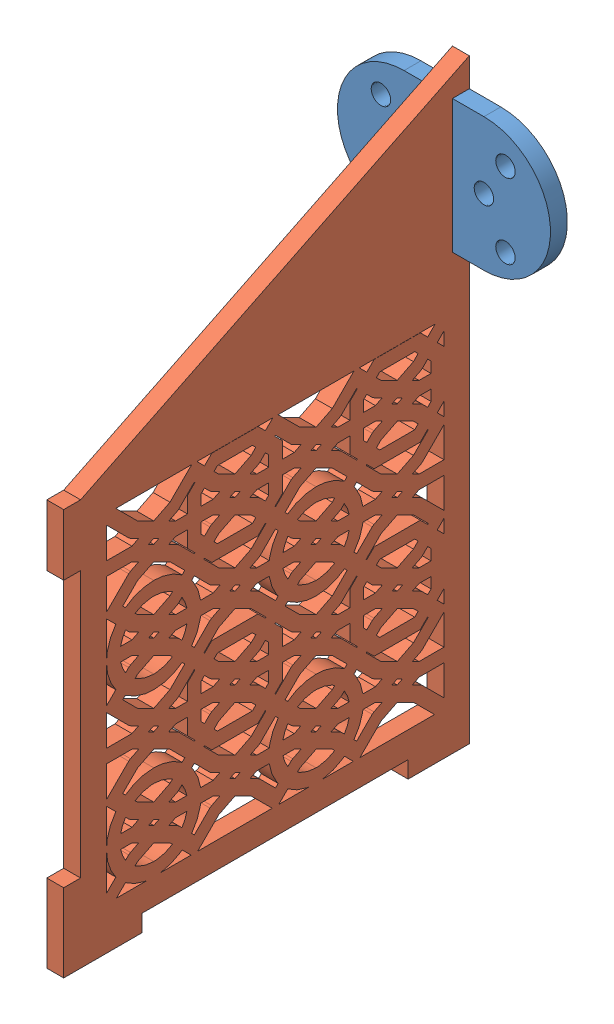
SolidWorks assembly Spicerack_bevel, configuration Default. Lengths in mm.
Overall size (40 111.89 76.17).
2 component instances, 2 part files, 3 mates.
Components (placement in the parent):
- Spicerack_mount_bevel-1: Spicerack_mount_bevel [Default] at (23.9298 22.164 25.0786) size (40 25 3.17)
- Spicerack_side_bevel-1: Spicerack_side_bevel [Default] at (5.9681 -22.8444 67.6943) x (0 0 1) z (-1 0 0) size (76.17 111.89 3.17)
Mates (geometry in assembly coordinates):
- Coincident1: coincident: plane of Spicerack_mount_bevel-1 through (-3.1194 19.4427 28.2536) normal (0 0 1); plane of Spicerack_side_bevel-1 through (2.7931 29.4427 28.2536) normal (0 0 -1)
- Coincident2: coincident: plane of Spicerack_mount_bevel-1 through (2.7931 9.4427 28.2536) normal (0 -1 0); plane of Spicerack_side_bevel-1 through (2.7931 9.4427 28.2536) normal (0 1 0)
- Coincident3: coincident anti-aligned: plane of Spicerack_mount_bevel-1 through (2.7931 31.9427 28.2536) normal (1 0 0); plane of Spicerack_side_bevel-1 through (2.7931 -22.8444 67.6943) normal (-1 0 0)
